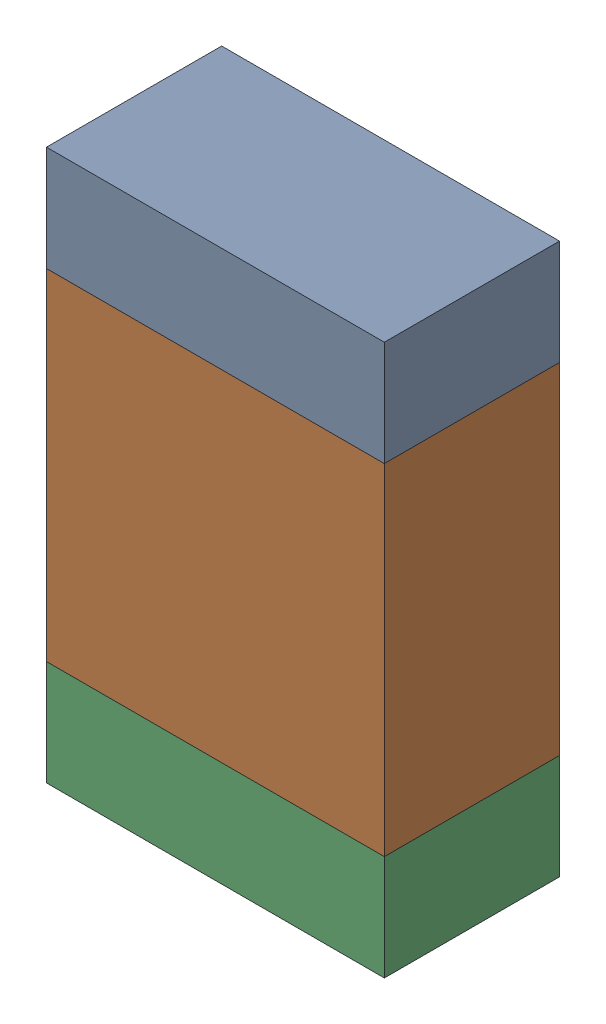
SolidWorks assembly R11, configuration Default. Lengths in mm.
Overall size (1.35 2.2 0.7).
6 component instances, 2 part files, 0 mates.
Components (placement in the parent):
- 959207304-1: 959207304 [Default] at (133.9849 94.0691 0) size (1.35 0.42 0.7)
  - Extruded-8-1: Extruded-8 [Default] at origin size (1.35 0.42 0.7)
- 959207440-1: 959207440 [Default] at (133.9849 93.1791 0) size (1.35 1.36 0.7)
  - Extruded-9-1: Extruded-9 [Default] at origin size (1.35 1.36 0.7)
- 959207304-2: 959207304 [Default] at (133.9849 92.2891 0) size (1.35 0.42 0.7)
  - Extruded-8-1: Extruded-8 [Default] at origin size (1.35 0.42 0.7)
